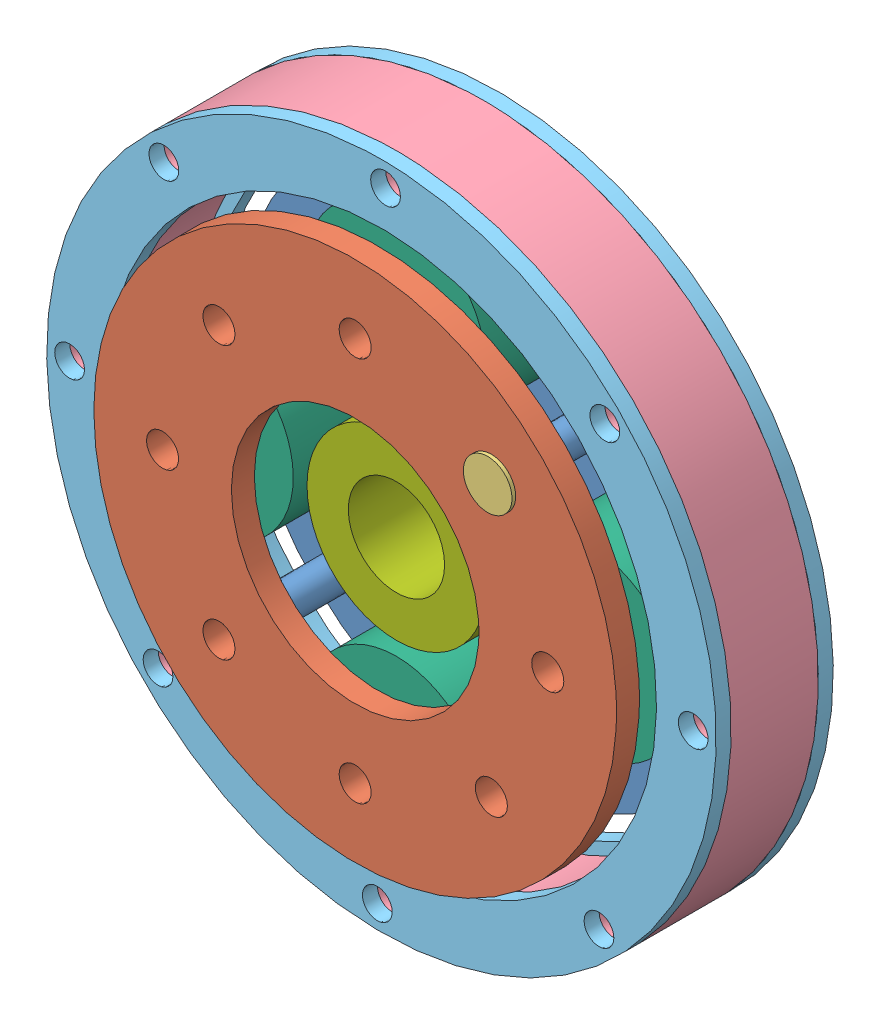
SolidWorks assembly Planetary Gearbox, configuration Default. Lengths in mm.
Overall size (147.92 147.92 46.8).
26 component instances, 7 part files, 25 mates.
Components (placement in the parent):
- Axle Plate-1: Axle Plate [Default] at (-81.2102 145.631 57.2035) size (114 114 34.35)
- Drive Plate-1: Drive Plate [Default] at (-81.2102 145.631 83.8535) size (114 114 5)
- Nut-1: Nut [Default] at (-51.5117 175.3295 89.6535) x (1 0 0) z (0 1 0) size (10.6 0.8 10.6)
- Ring-1: Ring [Default] at (-81.2102 145.631 79.8535) x (0.999913 -0.013212 0) z (0.013212 0.999913 0) size (146 19 146)
- Ring Cover-1: Ring Cover [Default] at (-81.2102 145.631 57.5785) x (0.999913 -0.013212 0) z (-0.013212 -0.999913 0) size (146 3.28 146)
- Ring Cover-2: Ring Cover [Default] at (-81.2102 145.631 83.1285) x (0.999913 -0.013212 0) z (0.013212 0.999913 0) size (146 3.28 146)
- Planet Gear-2: Planet Gear [Default] at (-39.2102 145.631 79.8535) x (1 0 0) z (0 1 0) size (39 19 39)
- Planet Gear-3: Planet Gear [Default] at (-123.2102 145.631 79.8535) x (0.475618 -0.879652 0) z (0.879652 0.475618 0) size (39 19 39)
- Planet Gear-4: Planet Gear [Default] at (-81.2102 103.631 79.8535) x (1 0 0) z (0 1 0) size (39 19 39)
- Planet Gear-5: Planet Gear [Default] at (-81.2102 187.631 79.8535) x (1 0 0) z (0 1 0) size (39 19 39)
- Nut-2: Nut [Default] at (-81.2102 187.631 89.6535) x (0.707107 0.707107 0) z (-0.707107 0.707107 0) size (10.6 0.8 10.6) (suppressed, hidden)
- Nut-3: Nut [Default] at (-110.9087 175.3295 89.6535) x (0 1 0) z (-1 0 0) size (10.6 0.8 10.6) (suppressed, hidden)
- Nut-4: Nut [Default] at (-123.2102 145.631 89.6535) x (-0.707107 0.707107 0) z (-0.707107 -0.707107 0) size (10.6 0.8 10.6) (suppressed, hidden)
- Nut-5: Nut [Default] at (-110.9087 115.9325 89.6535) x (-1 0 0) z (0 -1 0) size (10.6 0.8 10.6) (suppressed, hidden)
- Nut-6: Nut [Default] at (-81.2102 103.631 89.6535) x (-0.707107 -0.707107 0) z (0.707107 -0.707107 0) size (10.6 0.8 10.6) (suppressed, hidden)
- Nut-7: Nut [Default] at (-51.5117 115.9325 89.6535) x (0 -1 0) z (1 0 0) size (10.6 0.8 10.6) (suppressed, hidden)
- Nut-8: Nut [Default] at (-39.2102 145.631 89.6535) x (0.707107 -0.707107 0) z (0.707107 0.707107 0) size (10.6 0.8 10.6) (suppressed, hidden)
- Nut-9: Nut [Default] at (-51.5117 175.3295 52.2035) x (1 0 0) z (0 1 0) size (10.6 0.8 10.6)
- Nut-10: Nut [Default] at (-81.2102 187.631 52.2035) x (0.707107 0.707107 0) z (-0.707107 0.707107 0) size (10.6 0.8 10.6) (suppressed, hidden)
- Nut-11: Nut [Default] at (-110.9087 175.3295 52.2035) x (0 1 0) z (-1 0 0) size (10.6 0.8 10.6) (suppressed, hidden)
- Nut-12: Nut [Default] at (-123.2102 145.631 52.2035) x (-0.707107 0.707107 0) z (-0.707107 -0.707107 0) size (10.6 0.8 10.6) (suppressed, hidden)
- Nut-13: Nut [Default] at (-110.9087 115.9325 52.2035) x (-1 0 0) z (0 -1 0) size (10.6 0.8 10.6) (suppressed, hidden)
- Nut-14: Nut [Default] at (-81.2102 103.631 52.2035) x (-0.707107 -0.707107 0) z (0.707107 -0.707107 0) size (10.6 0.8 10.6) (suppressed, hidden)
- Nut-15: Nut [Default] at (-51.5117 115.9325 52.2035) x (0 -1 0) z (1 0 0) size (10.6 0.8 10.6) (suppressed, hidden)
- Nut-16: Nut [Default] at (-39.2102 145.631 52.2035) x (0.707107 -0.707107 0) z (0.707107 0.707107 0) size (10.6 0.8 10.6) (suppressed, hidden)
- Sun Gear-1: Sun Gear [Default] at (-81.2102 145.631 60.8535) size (39 39 19)
Mates (geometry in assembly coordinates):
- Concentric2: concentric anti-aligned: cylinder of Axle Plate-1 through (-123.2102 145.631 77.2035) axis (0 0 -1) radius 3.5; cylinder of Planet Gear-3 through (-123.2102 145.631 60.8535) axis (0 0 1) radius 3.5
- Concentric3: concentric anti-aligned: cylinder of Axle Plate-1 through (-81.2102 187.631 77.2035) axis (0 0 -1) radius 3.5; cylinder of Planet Gear-5 through (-81.2102 187.631 60.8535) axis (0 0 1) radius 3.5
- Concentric4: concentric anti-aligned: cylinder of Axle Plate-1 through (-39.2102 145.631 77.2035) axis (0 0 -1) radius 3.5; cylinder of Planet Gear-2 through (-39.2102 145.631 60.8535) axis (0 0 1) radius 3.5
- Concentric5: concentric anti-aligned: cylinder of Axle Plate-1 through (-81.2102 103.631 77.2035) axis (0 0 -1) radius 3.5; cylinder of Planet Gear-4 through (-81.2102 103.631 60.8535) axis (0 0 1) radius 3.5
- Coincident1: coincident aligned: plane of Planet Gear-3 through (-123.2102 145.631 79.8535) normal (0 0 1); plane of Planet Gear-5 through (-81.2102 187.631 79.8535) normal (0 0 1)
- Coincident2: coincident aligned: plane of Planet Gear-3 through (-123.2102 145.631 79.8535) normal (0 0 1); plane of Planet Gear-2 through (-39.2102 145.631 79.8535) normal (0 0 1)
- Coincident3: coincident anti-aligned: plane of Planet Gear-3 through (-123.2102 145.631 79.8535) normal (0 0 1); circle of Planet Gear-4
- Concentric6: concentric aligned: cylinder of Drive Plate-1 through (-123.2102 145.631 88.8535) axis (0 0 -1) radius 3.5; cylinder of Axle Plate-1 through (-123.2102 145.631 77.2035) axis (0 0 -1) radius 3.5
- Concentric7: concentric aligned: cylinder of Axle Plate-1 through (-110.9087 175.3295 77.2035) axis (0 0 -1) radius 3.5; cylinder of Drive Plate-1 through (-110.9087 175.3295 88.8535) axis (0 0 -1) radius 3.5
- Distance2: distance = 31.65 mm aligned: plane of Drive Plate-1 through (-81.2102 145.631 88.8535) normal (0 0 1); plane of Axle Plate-1 through (-81.2102 145.631 57.2035) normal (0 0 1)
- Concentric8: concentric anti-aligned: cylinder of Axle Plate-1 through (-81.2102 145.631 42.8535) axis (0 0 -1) radius 57; cylinder of Ring-1 through (-81.2102 145.631 60.8535) axis (0 0 1) radius 73
- Coincident7: coincident anti-aligned: plane of Ring-1 through (-81.2102 145.631 79.8535) normal (0 0 1); plane of Ring Cover-2 through (-81.2102 145.631 79.8535) normal (0 0 -1)
- Concentric9: concentric aligned: cylinder of Ring-1 through (-80.3118 213.625 60.8535) axis (0 0 1) radius 3.25; cylinder of Ring Cover-2 through (-80.3118 213.625 79.8535) axis (0 0 1) radius 3.25
- Concentric10: concentric aligned: cylinder of Ring-1 through (-128.654 194.3453 60.8535) axis (0 0 1) radius 3.25; cylinder of Ring Cover-2 through (-128.654 194.3453 79.8535) axis (0 0 1) radius 3.25
- Coincident8: coincident anti-aligned: plane of Ring-1 through (-81.2102 145.631 60.8535) normal (0 0 -1); plane of Ring Cover-1 through (-81.2102 145.631 60.8535) normal (0 0 1)
- Concentric11: concentric anti-aligned: cylinder of Ring-1 through (-32.4958 193.0748 60.8535) axis (0 0 1) radius 3.25; cylinder of Ring Cover-1 through (-32.4958 193.0748 60.8535) axis (0 0 -1) radius 3.25
- Concentric12: concentric anti-aligned: cylinder of Ring-1 through (-80.3118 213.625 60.8535) axis (0 0 1) radius 3.25; cylinder of Ring Cover-1 through (-80.3118 213.625 60.8535) axis (0 0 -1) radius 3.25
- Concentric13: concentric anti-aligned: cylinder of Axle Plate-1 through (-51.5117 175.3295 77.2035) axis (0 0 -1) radius 3.5; cylinder of Nut-1 through (-51.5117 175.3295 88.8535) axis (0 0 1) radius 5.3
- Coincident10: coincident anti-aligned: plane of Drive Plate-1 through (-81.2102 145.631 88.8535) normal (0 0 1); plane of Nut-1 through (-51.5117 175.3295 88.8535) normal (0 0 -1)
- Concentric14: concentric anti-aligned: cylinder of Axle Plate-1 through (-51.5117 175.3295 77.2035) axis (0 0 -1) radius 3.5; cylinder of Nut-9 through (-51.5117 175.3295 51.4035) axis (0 0 1) radius 5.3
- Coincident11: coincident anti-aligned: plane of Axle Plate-1 through (-81.2102 202.631 52.2035) normal (0 0 -1); plane of Nut-9 through (-51.5117 175.3295 52.2035) normal (0 0 1)
- Concentric15: concentric aligned: cylinder of Axle Plate-1 through (-81.2102 145.631 42.8535) axis (0 0 -1) radius 57; cylinder of Sun Gear-1 through (-81.2102 145.631 79.8535) axis (0 0 -1) radius 10.5
- Coincident12: coincident aligned: plane of Planet Gear-5 through (-81.2102 187.631 79.8535) normal (0 0 1); plane of Sun Gear-1 through (-81.2102 145.631 79.8535) normal (0 0 1)
- Coincident13: coincident aligned: plane of Ring-1 through (-81.2102 145.631 79.8535) normal (0 0 1); plane of Sun Gear-1 through (-81.2102 145.631 79.8535) normal (0 0 1)
- Distance3: distance = 18 mm aligned: plane of Sun Gear-1 through (-81.2102 145.631 60.8535) normal (0 0 -1); plane of Axle Plate-1 through (-81.2102 170.631 42.8535) normal (0 0 -1)
